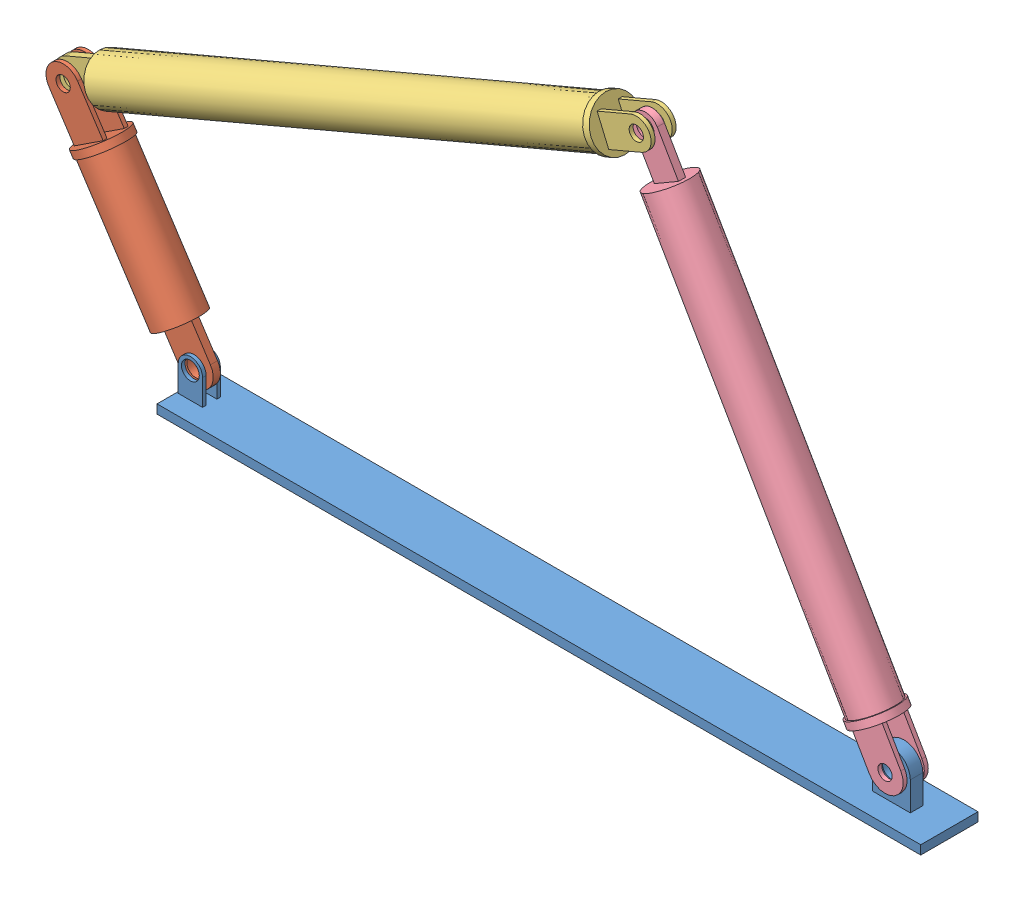
SolidWorks assembly 4Bar, configuration Default. Lengths in mm.
Overall size (504.92 276.72 32).
4 component instances, 4 part files, 7 mates.
Components (placement in the parent):
- Base-1: Base [Default] at (-234.1609 0 0) size (426.72 31.61 32)
- Link2-1: Link2 [Link1] at (-237.368 33.4213 0) x (-0.5485 0.836151 0) z (0 0 1) size (145.37 27.4 27.4)
- Link1-1: Link1 [Link1] at (-277.4585 129.9408 0) x (0.920291 0.391235 0) z (0 0 1) size (366.1 27.4 27.4)
- Link3-1: Link3 [Link1] at (36.4647 237.9199 0) x (0.501499 -0.865158 0) z (0 0 1) size (295.14 27.4 27.4)
Mates (geometry in assembly coordinates):
- Concentric1: concentric aligned: cylinder of Base-1; cylinder of Link2-1
- Coincident3: coincident aligned: plane of Base-1 through (-234.1609 0 0) normal (0 0 1); plane of Link2-1 through (-237.368 33.4213 0) normal (0 0 1)
- Concentric2: concentric aligned: cylinder of Link2-1; cylinder of Link1-1
- Coincident4: coincident aligned: plane of Link1-1 through (-277.4585 129.9408 0) normal (0 0 1); plane of assembly
- Concentric3: concentric aligned: cylinder of Link1-1; cylinder of Link3-1
- Coincident5: coincident aligned: plane of Link3-1 through (36.4647 237.9199 0) normal (0 0 1); plane of assembly
- Concentric4: concentric aligned: cylinder of Base-1; cylinder of Link3-1
